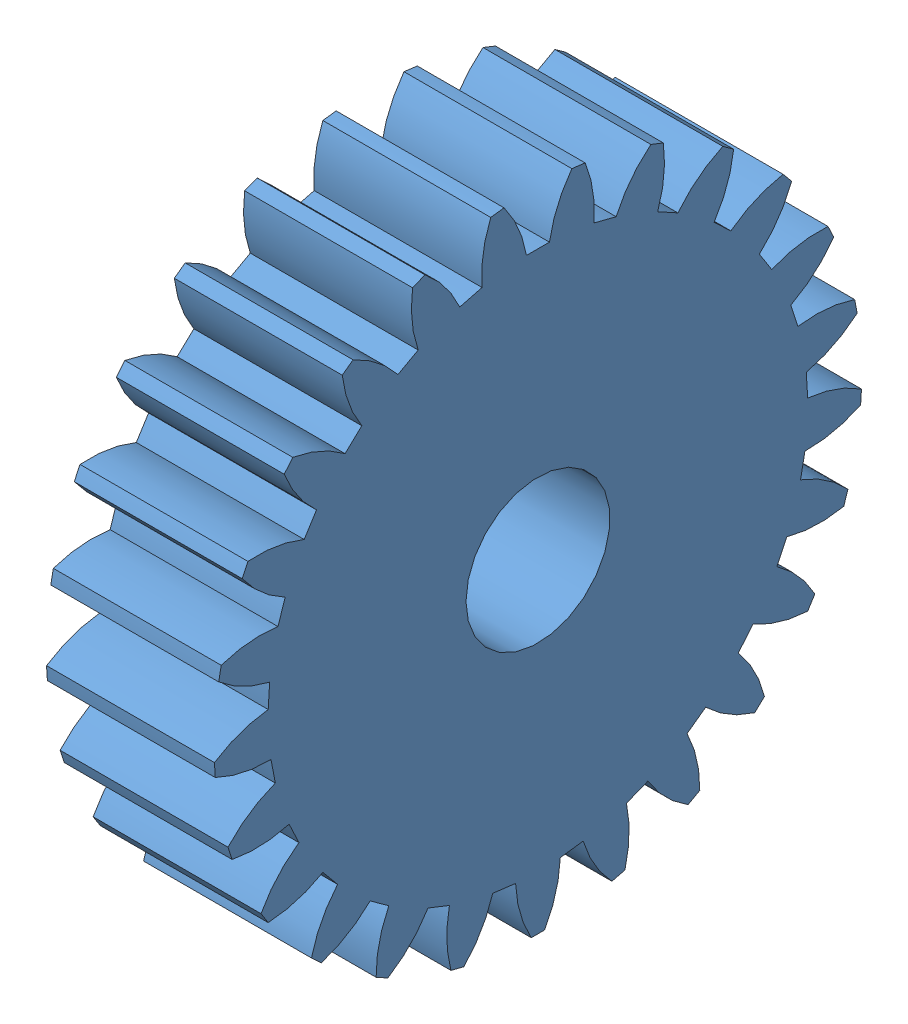
SolidWorks assembly spur newest, configuration Default. Lengths in mm.
Overall size (7 26.93 26.98).
2 component instances, 2 part files, 2 mates.
Components (placement in the parent):
- spur gear_am-3: spur gear_am [Metric - Spur gear 1M 25T 20PA 7FW ---S25N75H50L6N] at (-3.9809 -1.2518 1.1717) size (7 26.93 26.98)
- circle-1: circle [Default] at (13.0191 -1.2518 1.1717) x (0 1 0) z (0 0 1) (suppressed, hidden)
Mates (geometry in assembly coordinates):
- Coincident3: coincident: plane of spur gear_am-3 through (3.0191 -1.2518 1.1717) normal (1 0 0); plane of circle-1 through (3.0191 -1.2518 1.1717) normal (-1 0 0)
- Concentric1: concentric anti-aligned: circle of spur gear_am-3; circle of circle-1
